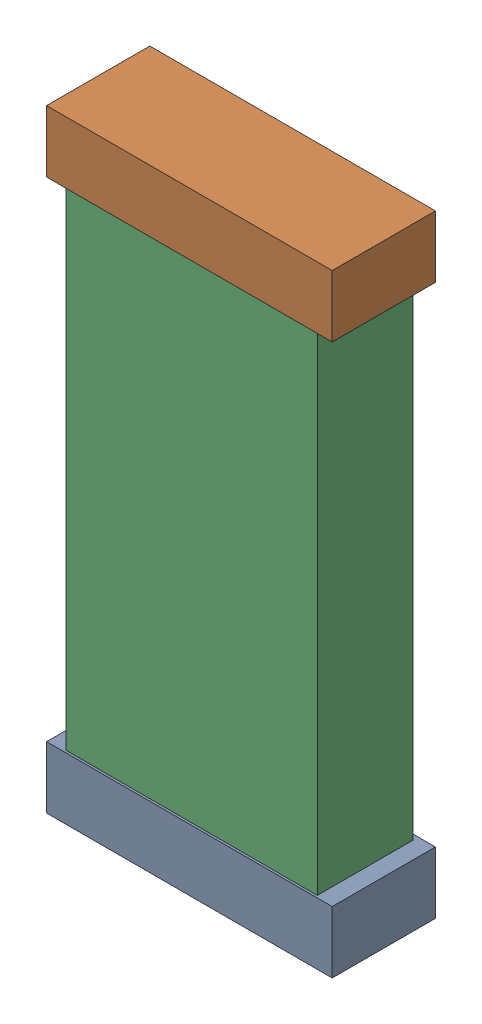
SolidWorks assembly C9, configuration Default. Lengths in mm.
Overall size (1.27 2.72 0.46).
6 component instances, 2 part files, 0 mates.
Components (placement in the parent):
- 804388560-1: 804388560 [Default] at (42.4207 18.7112 0.001) size (1.27 0.28 0.46)
  - Extruded (23)-1: Extruded (23) [Default] at origin size (1.27 0.28 0.46)
- 804388560_1-1: 804388560_1 [Default] at (42.4207 21.1601 0.001) size (1.27 0.28 0.46)
  - Extruded (23)-1: Extruded (23) [Default] at origin size (1.27 0.28 0.46)
- 804388688-1: 804388688 [Default] at (42.4207 19.8796 0.025) size (1.12 2.29 0.42)
  - Extruded (24)-1: Extruded (24) [Default] at origin size (1.12 2.29 0.42)
